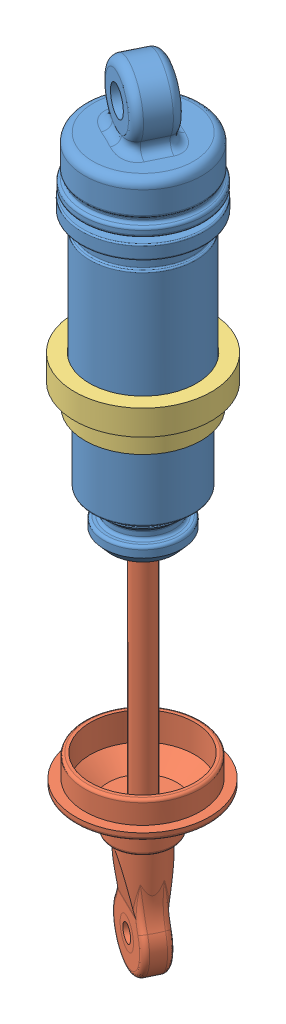
SolidWorks assembly ShockAbsorber, configuration Default. Lengths in mm.
Overall size (32.16 141.39 32.1).
4 component instances, 4 part files, 5 mates.
Components (placement in the parent):
- ShockBody^ShockAbsorber-2: ShockBody^ShockAbsorber [Default] at (-110.8156 118.4702 -126.402) x (0.898594 0 0.43878) z (-0.43878 0 0.898594) size (22.02 74.55 22) (virtual)
- Part4^ShockAbsorber-1: Part4^ShockAbsorber [Default] at (-111.2144 107.2476 -126.5968) x (-0.898594 0 -0.43878) z (0.43878 0 -0.898594) size (24 84.5 24) (virtual)
- SpringAdjuster^ShockAbsorber-1: SpringAdjuster^ShockAbsorber [Default] at (-111.0405 99.3643 -126.5119) x (0.373644 0 -0.927572) z (0.927572 0 0.373644) size (24.5 8.5 24.5) (virtual)
- Spring^ShockAbsorber-2: Spring^ShockAbsorber [Default] at (-34.7976 -2.4454 -146.0502) x (0 1 0) z (0 0 -1) (virtual)
Mates (geometry in assembly coordinates):
- Concentric1: concentric anti-aligned: cylinder of ShockBody^ShockAbsorber-2 through (-111.0405 102.079 -126.5119) axis (0 -1 0) radius 2; cylinder of Part4^ShockAbsorber-1 through (-111.0405 112.739 -126.5119) axis (0 1 0) radius 2
- LimitDistance1: limit distance = 42.34 mm anti-aligned: plane of ShockBody^ShockAbsorber-2 through (-111.0405 95.079 -126.5119) normal (0 -1 0); plane of Part4^ShockAbsorber-1 through (-110.9895 52.739 -126.487) normal (0 1 0)
- Parallel1: parallel aligned: plane of ShockBody^ShockAbsorber-2 through (-112.3513 118.4702 -123.2569) normal (-0.43878 0 0.898594); plane of Part4^ShockAbsorber-1 through (-111.9548 34.239 -124.51) normal (-0.43878 0 0.898594)
- Concentric2: concentric anti-aligned: cylinder of ShockBody^ShockAbsorber-2 through (-111.0405 163.629 -126.5119) axis (0 1 0) radius 9.5; cylinder of SpringAdjuster^ShockAbsorber-1 through (-111.0405 56.9649 -126.5119) axis (0 -1 0) radius 9.6
- Distance1: distance = 22 mm anti-aligned: plane of SpringAdjuster^ShockAbsorber-1 through (-106.4633 123.779 -137.8746) normal (0 1 0); plane of ShockBody^ShockAbsorber-2 through (-110.8156 145.779 -126.402) normal (0 -1 0)
